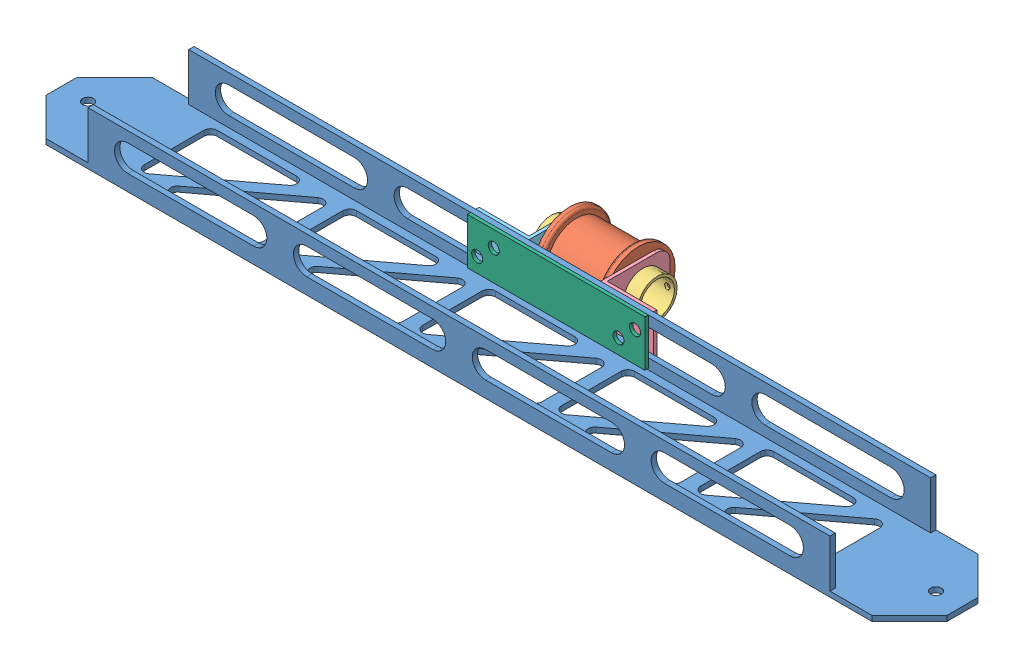
SolidWorks assembly Cross_Bar_Assem, configuration Default. Lengths in mm.
Overall size (431.8 34.92 87.09).
6 component instances, 6 part files, 14 mates.
Components (placement in the parent):
- Cross_Bar_with_Holes-1: Cross_Bar_with_Holes [Default] at (248.975 -13.1462 0) x (0 0 1) z (-1 0 0) size (50.8 25.4 431.8)
- Idle_Roller-1: Idle_Roller [Default] at (19.74 -0.4462 -18.8307) size (33.02 34.92 34.92)
- Idler_Axel-1: Idler_Axel [Default] at (58.475 -0.4462 -18.8307) x (0 -0.998678 0.051409) z (-1 0 0) size (19.05 19.05 50.8)
- Idler_Support_Left-1: Idler_Support_Left [Default] at (50.1289 -13.1462 0) x (0 1 0) z (-1 0 0) size (25.4 31.75 25.4)
- Idler_Support-2: Idler_Support [Default] at (15.7627 12.2538 0) x (0 -1 0) z (1 0 0) size (25.4 31.75 25.4)
- Idler_Mount_Plate-1: Idler_Mount_Plate [Default] at (-9.6373 -9.9712 2.54) x (1 0 0) z (0 -1 0) size (85.17 1.59 22.23)
Mates (geometry in assembly coordinates):
- Concentric1: concentric anti-aligned: cylinder of Idle_Roller-1 through (46.41 -0.4462 -20.7318) axis (-1 0 0) radius 9.9695; cylinder of Idler_Axel-1 through (4.9876 2.7724 -25.713) axis (1 0 0) radius 9.525
- Coincident1: coincident anti-aligned: plane of Cross_Bar_with_Holes-1 through (-182.825 -13.1462 0) normal (0 0 -1); plane of assembly through (0 0 0) normal (0 0 1)
- Coincident2: coincident aligned: plane of Cross_Bar_with_Holes-1 through (248.975 -0.4462 0) normal (0 1 0); plane of Idle_Roller-1 through (19.74 -0.4462 -20.7318) normal (0 1 0)
- Width1: width anti-aligned: plane of Idle_Roller-1 through (16.565 -0.4462 -20.7318) normal (-1 0 0); plane of Idle_Roller-1 through (49.585 -0.4462 -20.7318) normal (1 0 0); plane of Cross_Bar_with_Holes-1 through (210.875 -74.1062 0) normal (1 0 0); plane of Cross_Bar_with_Holes-1 through (-144.725 -74.1062 0) normal (-1 0 0)
- Width2: width anti-aligned: plane of Idle_Roller-1 through (16.565 -0.4462 -20.7318) normal (-1 0 0); plane of Idle_Roller-1 through (49.585 -0.4462 -20.7318) normal (1 0 0); plane of Idler_Axel-1 through (55.7876 2.7724 -25.713) normal (1 0 0); plane of Idler_Axel-1 through (4.9876 2.7724 -25.713) normal (-1 0 0)
- Coincident3: coincident anti-aligned: plane of Cross_Bar_with_Holes-1 through (-182.825 -13.1462 0) normal (0 0 -1); plane of Idler_Support_Left-1 through (50.1289 12.2538 0) normal (0 0 1)
- Coincident4: coincident aligned: plane of Cross_Bar_with_Holes-1 through (-182.825 12.2538 0) normal (0 1 0); plane of Idler_Support_Left-1 through (50.1289 12.2538 0) normal (0 1 0)
- Coincident5: coincident anti-aligned: plane of Cross_Bar_with_Holes-1 through (-182.825 -13.1462 0) normal (0 0 -1); plane of Idler_Support-2 through (15.7627 -13.1462 0) normal (0 0 1)
- Coincident7: coincident aligned: plane of Cross_Bar_with_Holes-1 through (-182.825 12.2538 0) normal (0 1 0); plane of Idler_Support-2 through (15.7627 12.2538 0) normal (0 1 0)
- Coincident8: coincident anti-aligned: plane of Cross_Bar_with_Holes-1 through (-182.825 -10.6062 2.54) normal (0 0 1); plane of Idler_Mount_Plate-1 through (-9.6373 -9.9712 2.54) normal (0 0 -1)
- Coincident9: coincident aligned: plane of Cross_Bar_with_Holes-1 through (-182.825 12.2538 0) normal (0 1 0); plane of Idler_Mount_Plate-1 through (-9.6373 12.2538 4.1275) normal (0 1 0)
- Coincident10: coincident aligned: plane of Idler_Support-2 through (-9.6373 -13.1462 0) normal (-1 0 0); plane of Idler_Mount_Plate-1 through (-9.6373 -9.9712 4.1275) normal (-1 0 0)
- Coincident11: coincident aligned: plane of Idler_Support_Left-1 through (75.5289 12.2538 0) normal (1 0 0); plane of Idler_Mount_Plate-1 through (75.5289 -9.9712 4.1275) normal (1 0 0)
- Concentric2: concentric aligned: circle of Idler_Axel-1; circle of Idler_Support-2
